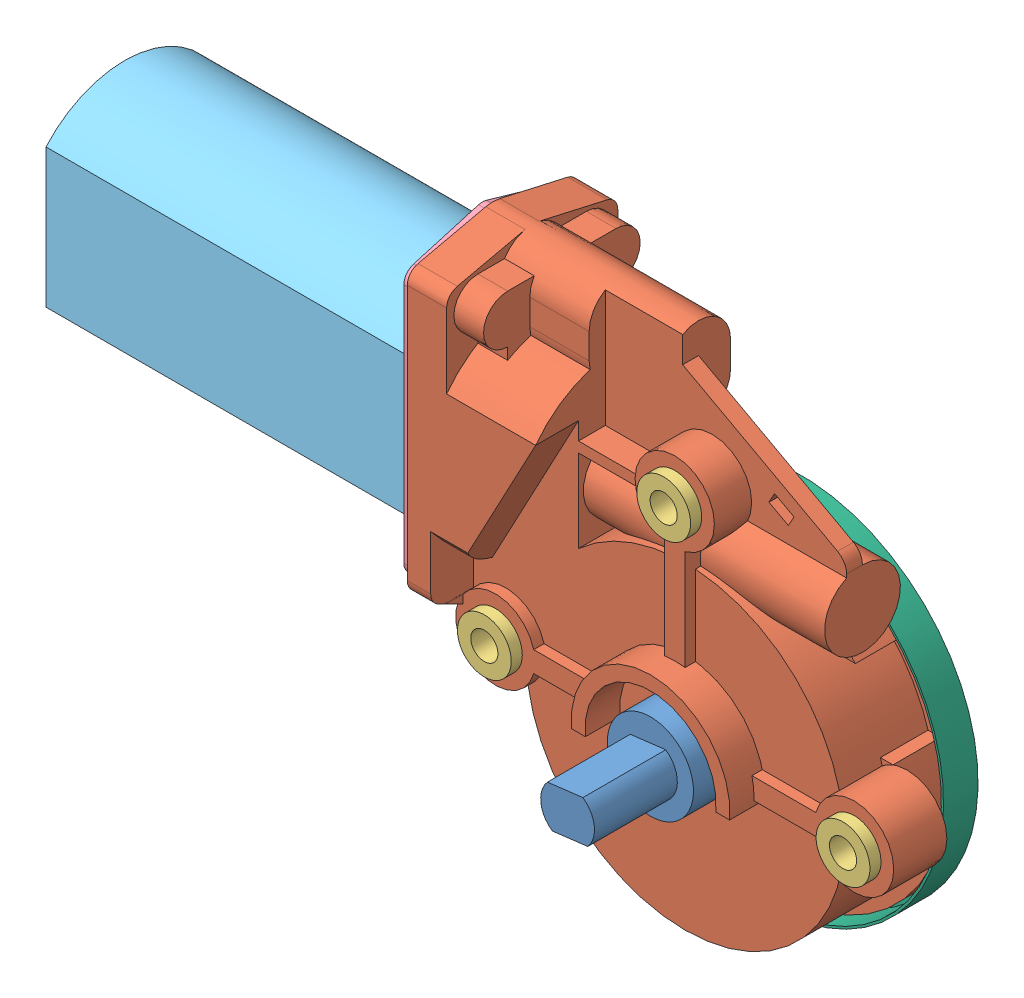
SolidWorks assembly WindowMotor, configuration Default. Lengths in mm.
Overall size (163.79 107.45 45.24).
9 component instances, 6 part files, 13 mates.
Components (placement in the parent):
- WindowMotor_OutputShaft-1: WindowMotor_OutputShaft [Default] at (-98.843 -78.1519 92.4963) x (0.121243 -0.992623 0) z (0 0 1) size (15.85 15.85 21.62)
- WindowMotor_GearboxHousing-1: WindowMotor_GearboxHousing [Default] at (-98.843 -78.1519 72.7859) size (83.55 92.74 31.5)
- WindowMotor_ThreadedInsert-1: WindowMotor_ThreadedInsert [Default] at (-98.843 -38.1617 72.7859) x (-0.364272 0.931293 0) z (0 0 1) size (9.91 9.91 11.94)
- WindowMotor_Motor-1: WindowMotor_Motor [Default] at (-207.6651 -49.1115 18.7981) x (0 0 1) z (-1 0 0) size (28.96 59.84 74.35)
  - WindowMotor_Motor2-1: WindowMotor_Motor2 [Default] at (44.2087 1.4883 0.2583) size (28.96 59.84 1.91)
  - WindowMotor_Motor1-1: WindowMotor_Motor1 [Default] at (44.2087 1.5352 2.1633) size (28.96 38.61 72.44)
- WindowMotor_ThreadedInsert-2: WindowMotor_ThreadedInsert [Default] at (-131.843 -76.6519 72.7859) x (0.528971 -0.84864 0) z (0 0 1) size (9.91 9.91 11.94)
- WindowMotor_ThreadedInsert-3: WindowMotor_ThreadedInsert [Default] at (-65.843 -76.6519 72.7859) x (-0.669835 -0.74251 0) z (0 0 1) size (9.91 9.91 11.94)
- WindowMotor_GearCap-1: WindowMotor_GearCap [Default] at (-98.843 -78.1519 50.4339) x (-0.73689 0.676012 0) z (0 0 1) size (65.41 65.41 6.35)
Mates (geometry in assembly coordinates):
- Coincident1: coincident anti-aligned: plane of WindowMotor_GearboxHousing-1 through (-142.0865 -101.9655 63.0069) normal (-1 0 0); plane of WindowMotor_Motor-1/WindowMotor_Motor2-1 through (-142.0865 -47.7502 11.0852) normal (1 0 0)
- Width1: width aligned: plane of WindowMotor_GearboxHousing-1 through (-142.0865 -101.9655 47.2589) normal (0 0 -1); plane of WindowMotor_GearboxHousing-1 through (-142.0865 -101.9655 78.7549) normal (0 0 1); plane of WindowMotor_Motor-1/WindowMotor_Motor2-1 through (-143.9915 -47.7502 48.5289) normal (0 0 -1); plane of WindowMotor_Motor-1/WindowMotor_Motor2-1 through (-143.9915 -47.7502 77.4849) normal (0 0 1)
- Distance1: distance = 1.016 mm aligned: plane of WindowMotor_Motor-1/WindowMotor_Motor2-1 through (-143.9915 -77.7222 11.0852) normal (0 -1 0); plane of WindowMotor_GearboxHousing-1 through (-134.8475 -78.7382 63.0069) normal (0 -1 0)
- Concentric2: concentric aligned: cylinder of WindowMotor_GearboxHousing-1 through (-98.843 -38.1617 63.0069) axis (0 0 1) radius 2.54; cylinder of WindowMotor_ThreadedInsert-1 through (-98.843 -38.1617 62.8799) axis (0 0 1) radius 3.175
- Coincident4: coincident anti-aligned: plane of WindowMotor_GearboxHousing-1 through (-99.5127 -135.4468 72.7859) normal (0 0 1); plane of WindowMotor_ThreadedInsert-1 through (-98.843 -38.1617 72.7859) normal (0 0 -1)
- Concentric3: concentric anti-aligned: circle of WindowMotor_GearboxHousing-1; cylinder of WindowMotor_ThreadedInsert-2 through (-131.843 -76.6519 62.8799) axis (0 0 1) radius 3.175
- Coincident5: coincident anti-aligned: plane of WindowMotor_GearboxHousing-1 through (-99.5127 -135.4468 72.7859) normal (0 0 1); plane of WindowMotor_ThreadedInsert-2 through (-131.843 -76.6519 72.7859) normal (0 0 -1)
- Coincident7: coincident anti-aligned: plane of WindowMotor_GearboxHousing-1 through (-98.843 -78.1519 50.4339) normal (0 0 -1); plane of WindowMotor_GearCap-1 through (-98.843 -78.1519 50.4339) normal (0 0 1)
- Concentric4: concentric aligned: cylinder of WindowMotor_GearboxHousing-1 through (-98.843 -78.1519 129.2753) axis (0 0 -1) radius 31.496; cylinder of WindowMotor_GearCap-1 through (-98.843 -78.1519 56.0219) axis (0 0 -1) radius 32.2961
- Concentric5: concentric aligned: cylinder of WindowMotor_OutputShaft-1 through (-98.843 -78.1519 70.8809) axis (0 0 1) radius 7.9248; cylinder of WindowMotor_GearboxHousing-1 through (-98.843 -78.1519 50.4339) axis (0 0 1) radius 5.461
- Coincident8: coincident anti-aligned: plane of WindowMotor_OutputShaft-1 through (-98.843 -78.1519 70.8809) normal (0 0 -1); plane of WindowMotor_GearboxHousing-1 through (-98.843 -78.1519 70.8809) normal (0 0 1)
- Concentric6: concentric aligned: cylinder of WindowMotor_GearboxHousing-1 through (-65.843 -76.6519 63.0069) axis (0 0 1) radius 2.54; cylinder of WindowMotor_ThreadedInsert-3 through (-65.843 -76.6519 62.8799) axis (0 0 1) radius 3.175
- Coincident9: coincident anti-aligned: plane of WindowMotor_GearboxHousing-1 through (-99.5127 -135.4468 72.7859) normal (0 0 1); plane of WindowMotor_ThreadedInsert-3 through (-65.843 -76.6519 72.7859) normal (0 0 -1)
